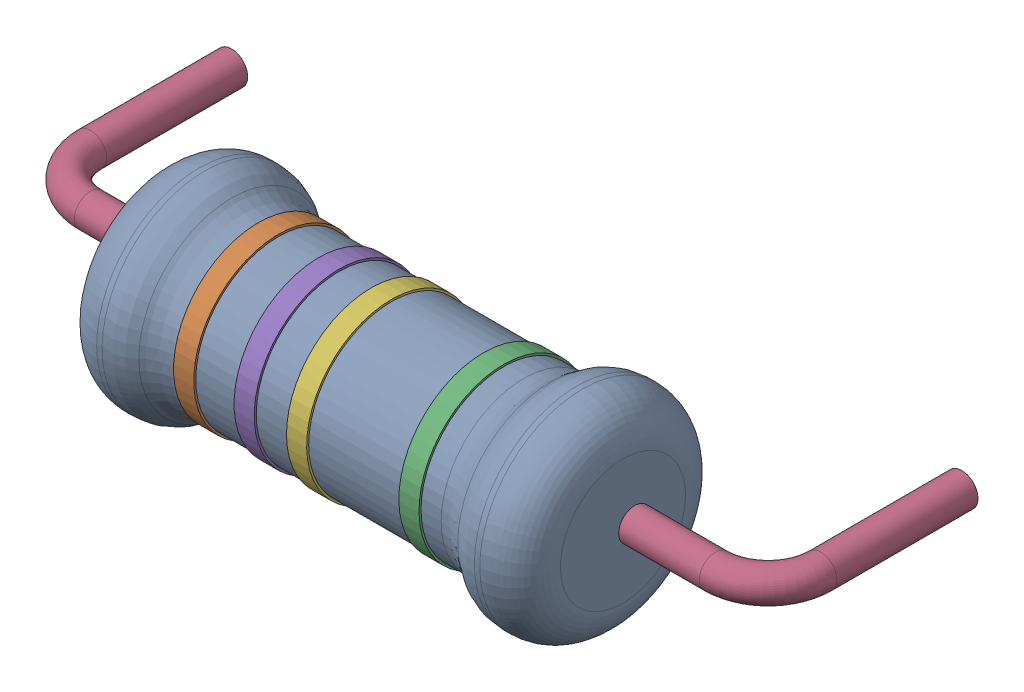
SolidWorks assembly Res_Yageo_KNP100JR-73-22R_eec.step, configuration Default. Lengths in mm.
Overall size (18.91 5.72 7.96).
6 component instances, 6 part files, 0 mates.
Components (placement in the parent):
- 1.step-1: 1.step [Default] at (0 0 2.55) size (11.5 5.1 5.1)
- 2.step-1: 2.step [Default] at (-3.2931 0 2.55) x (0 0 -1) z (1 0 0) size (4.2 4.2 0.5)
- 3.step-1: 3.step [Default] at (2.7931 0 2.55) x (0 -0.492137 0.870518) z (-1 0 0) size (4.2 4.2 0.5)
- 4.step-1: 4.step [Default] at (0 0 -2.55) size (18.91 0.8 5.21)
- 5.step-1: 5.step [Default] at (-1.7931 0 2.55) x (0 0 -1) z (1 0 0) size (4.2 4.2 0.5)
- 6.step-1: 6.step [Default] at (0.0069 0 2.55) x (0 -0.017206 0.999852) z (-1 0 0) size (4.2 4.2 0.5)
